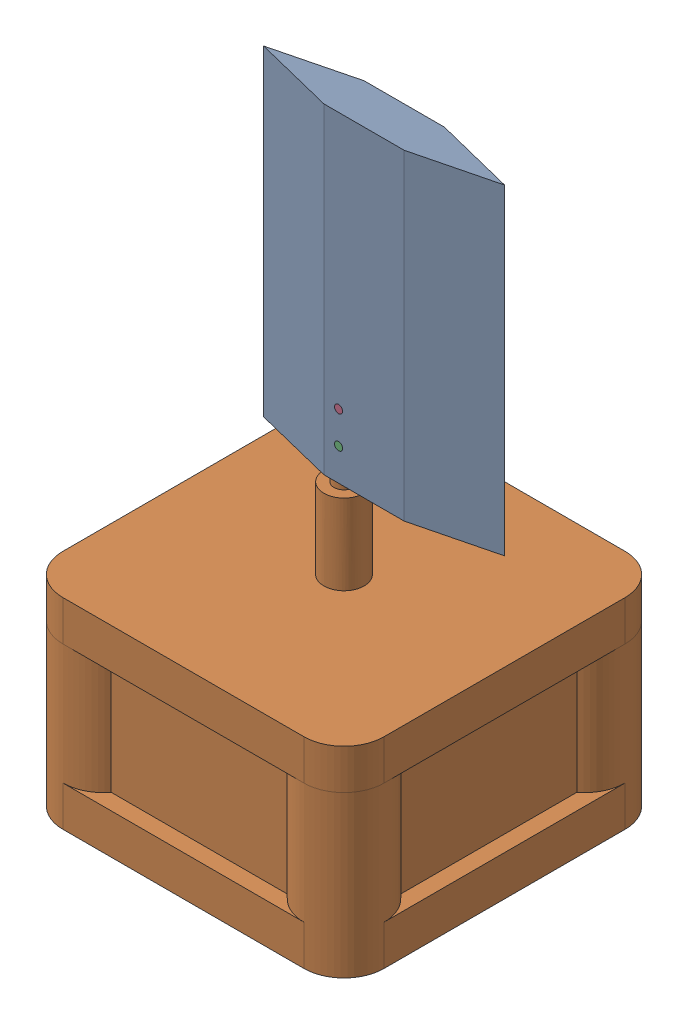
SolidWorks assembly Roll Tab Assembly, configuration Default. Lengths in mm.
Overall size (50.8 97.79 50.8).
4 component instances, 3 part files, 8 mates.
Components (placement in the parent):
- Roll Tab-1: Roll Tab [Default] at (-4.2264 -9.1749 8.4635) size (38.1 50.8 6.35)
- Motor Ex Roll Tab-1: Motor Ex Roll Tab [Default] at (-29.6264 -56.1649 30.6885) size (50.8 63.5 50.8)
- Roll Tab Pin-1: Roll Tab Pin [Default] at (-1.9112 -4.0949 8.4635) x (0 0 -1) z (1 0 0) size (3.81 1.27 1.27)
- Roll Tab Pin-2: Roll Tab Pin [Default] at (-1.9112 0.9851 8.4635) x (0 0 -1) z (1 0 0) size (3.81 1.27 1.27)
Mates (geometry in assembly coordinates):
- Concentric1: concentric aligned: cylinder of Roll Tab-1 through (-4.2264 7.3351 5.2885) axis (0 -1 0) radius 1.5875; cylinder of Motor Ex Roll Tab-1 through (-4.2264 7.3351 5.2885) axis (0 -1 0) radius 1.5875
- Parallel1: parallel anti-aligned: plane of Roll Tab-1 through (-1.0514 7.3351 5.9235) normal (-1 0 0); plane of Motor Ex Roll Tab-1 through (-1.0514 7.3351 4.6535) normal (1 0 0)
- Coincident2: coincident anti-aligned: plane of Roll Tab-1 through (-4.2264 7.3351 5.2885) normal (0 -1 0); plane of Motor Ex Roll Tab-1 through (-4.2264 7.3351 5.2885) normal (0 1 0)
- Concentric2: concentric aligned: cylinder of Roll Tab-1 through (-1.9112 -4.0949 5.2885) axis (0 0 1) radius 0.635; cylinder of Roll Tab Pin-1 through (-1.9112 -4.0949 4.6535) axis (0 0 1) radius 0.635
- Coincident3: coincident aligned: plane of Roll Tab-1 through (-4.2264 41.6251 8.4635) normal (0 0 1); plane of Roll Tab Pin-1 through (-1.9112 -4.0949 8.4635) normal (0 0 1)
- Coincident4: coincident aligned: plane of Roll Tab-1 through (-4.2264 41.6251 8.4635) normal (0 0 1); plane of Roll Tab Pin-1 through (-1.9112 -4.0949 8.4635) normal (0 0 1)
- Concentric3: concentric: cylinder of Roll Tab-1 through (-1.9112 0.9851 5.2885) axis (0 0 1) radius 0.635; cylinder of Roll Tab Pin-2 through (-1.9112 0.9851 5.8698) axis (0 0 1) radius 0.635
- Coincident5: coincident aligned: plane of Roll Tab-1 through (-4.2264 41.6251 8.4635) normal (0 0 1); plane of Roll Tab Pin-2 through (-1.9112 0.9851 8.4635) normal (0 0 1)
